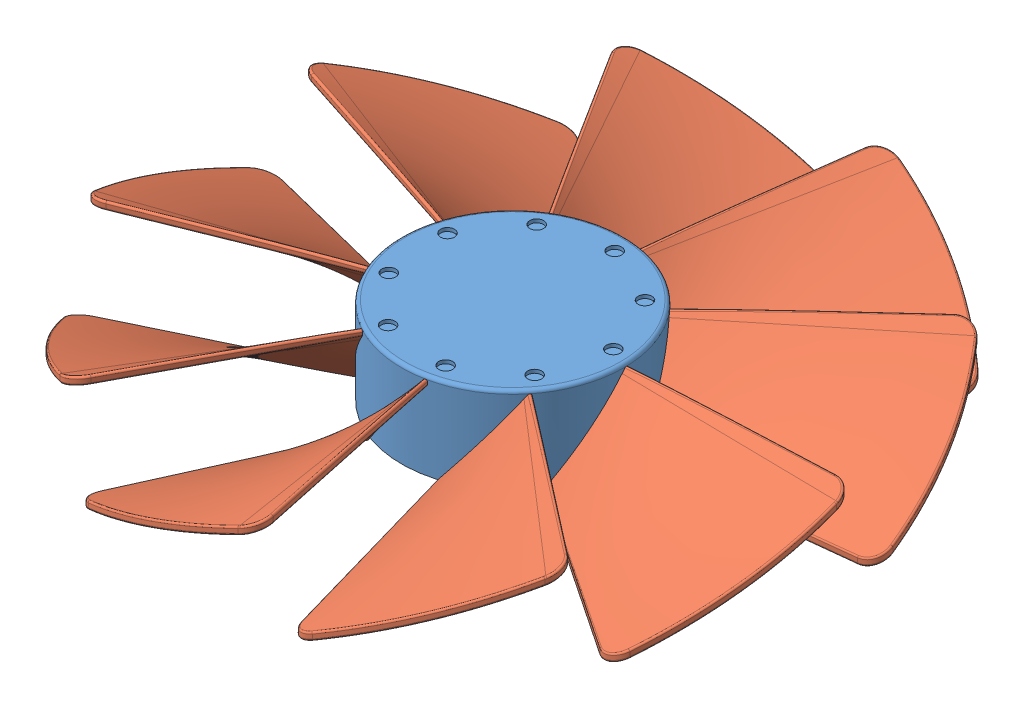
SolidWorks assembly NF-A20-Rotor, configuration Standard. Lengths in mm.
Overall size (214.05 28.34 214.61).
10 component instances, 2 part files, 6 mates.
Components (placement in the parent):
- NF-A20-Rotor-Core-1: NF-A20-Rotor-Core [Standard] at (-32 -30 32) x (0.999376 0 -0.035329) z (0.035329 0 0.999376) size (64 25 64)
- NF-A20-Rotor-Fin-1: NF-A20-Rotor-Fin [Standard] at (-33.0712 -30.212 32.0423) x (0.970961 -0.007209 0.239128) z (-0.23919 -0.009447 0.970927) size (68.87 27.34 53.71)
- NF-A20-Rotor-Fin-2: NF-A20-Rotor-Fin [Standard] at (-32.8478 -30.212 31.3438) x (0.590091 -0.007209 0.807305) z (-0.80733 -0.009447 0.590025) size (68.87 27.34 53.71)
- NF-A20-Rotor-Fin-3: NF-A20-Rotor-Fin [Standard] at (-32.2277 -30.212 30.9524) x (-0.06689 -0.007209 0.997734) z (-0.997711 -0.009447 -0.066957) size (68.87 27.34 53.71)
- NF-A20-Rotor-Fin-4: NF-A20-Rotor-Fin [Standard] at (-31.501 -30.212 31.0512) x (-0.692572 -0.007209 0.721313) z (-0.721252 -0.009447 -0.692608) size (68.87 27.34 53.71)
- NF-A20-Rotor-Fin-5: NF-A20-Rotor-Fin [Standard] at (-31.0079 -30.212 31.5939) x (-0.994192 -0.007209 0.107381) z (-0.107311 -0.009447 -0.994181) size (68.87 27.34 53.71)
- NF-A20-Rotor-Fin-6: NF-A20-Rotor-Fin [Standard] at (-30.9789 -30.212 32.3266) x (-0.830618 -0.007209 -0.556796) z (0.556842 -0.009447 -0.830565) size (68.87 27.34 53.71)
- NF-A20-Rotor-Fin-7: NF-A20-Rotor-Fin [Standard] at (-31.4278 -30.212 32.9066) x (-0.278389 -0.007209 -0.960441) z (0.960442 -0.009447 -0.278319) size (68.87 27.34 53.71)
- NF-A20-Rotor-Fin-8: NF-A20-Rotor-Fin [Standard] at (-32.1444 -30.212 33.0623) x (0.404101 -0.007209 -0.914686) z (0.914641 -0.009447 0.404156) size (68.87 27.34 53.71)
- NF-A20-Rotor-Fin-9: NF-A20-Rotor-Fin [Standard] at (-32.7934 -30.212 32.7209) x (0.897508 -0.007209 -0.440939) z (0.440869 -0.009447 0.897522) size (68.87 27.34 53.71)
Mates (geometry in assembly coordinates):
- Deckungsgleich1: coincident: cylinder of NF-A20-Rotor-Core-1 through (-32 -30 32) axis (0 1 0) radius 32; point of NF-A20-Rotor-Fin-1
- Deckungsgleich2: coincident: cylinder of NF-A20-Rotor-Core-1 through (-32 -30 32) axis (0 1 0) radius 32; point of NF-A20-Rotor-Fin-1
- Tangential5: tangent: circle of NF-A20-Rotor-Core-1; curve of NF-A20-Rotor-Fin-1
- Deckungsgleich5: coincident aligned: plane of NF-A20-Rotor-Core-1 through (-32 0 32) normal (0 1 0); plane of assembly through (0 0 0) normal (0 1 0)
- Tangential9: tangent anti-aligned: cylinder of NF-A20-Rotor-Core-1 through (-32 -30 32) axis (0 1 0) radius 32; plane of assembly through (0 0 0) normal (0 0 1)
- Tangential10: tangent aligned: cylinder of NF-A20-Rotor-Core-1 through (-32 -30 32) axis (0 1 0) radius 32; plane of assembly through (0 0 0) normal (1 0 0)
